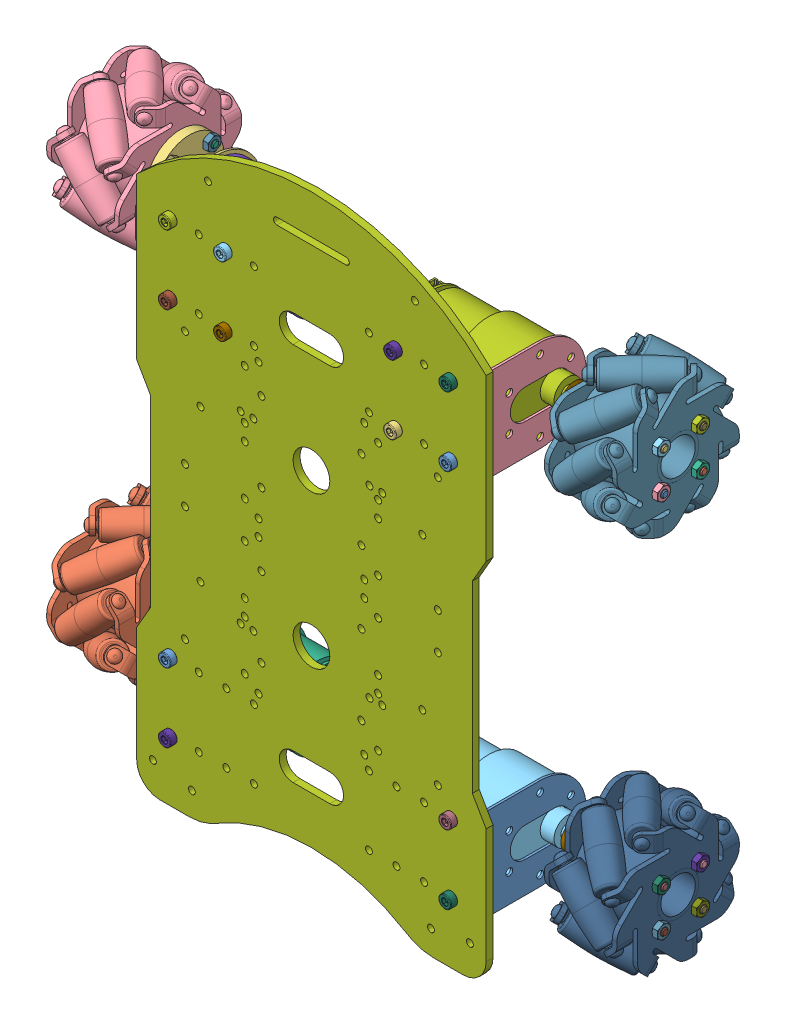
SolidWorks assembly mkbot_sw_carkit, configuration Varsayılan. Lengths in mm.
Overall size (254 262.05 67.79).
125 component instances, 97 part files, 0 mates.
Components (placement in the parent):
- Motor Brackets-1: Motor Brackets [Varsayılan] at origin size (142 205 45.5)
  - Motor Bracket_001-1: Motor Bracket_001 [Varsayılan] at (71 -115.5 -4) x (-1 0 0) z (0 0 -1) size (41 40 45.5)
  - Motor Bracket_002-1: Motor Bracket_002 [Varsayılan] at (-71 -115.5 -4) x (1 0 0) z (0 0 -1) size (41 40 45.5)
  - Motor Bracket_003-1: Motor Bracket_003 [Varsayılan] at (-71 49.5 -4) x (1 0 0) z (0 0 -1) size (41 40 45.5)
  - Motor Bracket_004-1: Motor Bracket_004 [Varsayılan] at (71 49.5 -4) x (-1 0 0) z (0 0 -1) size (41 40 45.5)
- Motors-1: Motors [Varsayılan] at origin size (182 202 37)
  - DC Gear Motor 37mm_001-1: DC Gear Motor 37mm_001 [Varsayılan] at (79 -115.5 -28.5) x (0 0 -1) z (1 0 0) size (37 37 73.8)
  - DC Gear Motor 37mm_002-1: DC Gear Motor 37mm_002 [Varsayılan] at (-79 -115.5 -28.5) x (0 0 -1) z (-1 0 0) size (37 37 73.8)
  - DC Gear Motor 37mm_003-1: DC Gear Motor 37mm_003 [Varsayılan] at (79 49.5 -28.5) x (0 0 -1) z (1 0 0) size (37 37 73.8)
  - DC Gear Motor 37mm_004-1: DC Gear Motor 37mm_004 [Varsayılan] at (-79 49.5 -28.5) x (0 0 -1) z (-1 0 0) size (37 37 73.8)
- Wheels-1: Wheels [Varsayılan] at origin size (254 223.31 58.31)
  - Rad_001-1: Rad_001 [Varsayılan] at (79 -115.5 -35.5) x (1 0 0) z (0 0 -1) size (48 58.31 58.31)
    - Rad 60mm_001-1: Rad 60mm_001 [Varsayılan] at (13.5 0 0) x (0 -1 0) z (0 0 1) size (58.31 48 58.31)
      - Rad Adapter_001-1: Rad Adapter_001 [Varsayılan] at origin size (30 33.5 30)
      - mecanum wheel_001-1: mecanum wheel_001 [Varsayılan] at (0 2 0) size (58.31 31.5 58.31)
      - Fasteners-1: Fasteners [Varsayılan] at origin size (23.35 44.66 22.5)
        - M3x41.5-ThreadedRod006-1: M3x41.5-ThreadedRod006 [Varsayılan] at (-8.5 -7 -8.5) x (0 0 -1) z (0 -1 0) size (3.03 3.03 41.5)
        - M3x41.5-ThreadedRod005-1: M3x41.5-ThreadedRod005 [Varsayılan] at (-8.5 -7 8.5) x (0 0 -1) z (0 -1 0) size (3.03 3.03 41.5)
        - M3x41.5-ThreadedRod004-1: M3x41.5-ThreadedRod004 [Varsayılan] at (8.5 -7 -8.5) x (0 0 -1) z (0 -1 0) size (3.03 3.03 41.5)
        - M3-Nut008-1: M3-Nut008 [Varsayılan] at (-8.5 31.5 -8.5) x (1 0 0) z (0 1 0) size (6.35 5.5 2.4)
        - M3-Nut007-1: M3-Nut007 [Varsayılan] at (8.5 31.5 -8.5) x (1 0 0) z (0 1 0) size (6.35 5.5 2.4)
        - M3-Nut006-1: M3-Nut006 [Varsayılan] at (-8.5 31.5 8.5) x (1 0 0) z (0 1 0) size (6.35 5.5 2.4)
        - M3-Nut005-1: M3-Nut005 [Varsayılan] at (8.5 31.5 8.5) x (1 0 0) z (0 1 0) size (6.35 5.5 2.4)
        - M3-Nut-1: M3-Nut [Varsayılan] at (-8.5 -4 -8.5) x (1 0 0) z (0 -1 0) size (6.35 5.5 2.4)
        - M3-Nut003-1: M3-Nut003 [Varsayılan] at (8.5 -4 -8.5) x (1 0 0) z (0 -1 0) size (6.35 5.5 2.4)
        - M3-Nut002-1: M3-Nut002 [Varsayılan] at (-8.5 -4 8.5) x (1 0 0) z (0 -1 0) size (6.35 5.5 2.4)
        - M3-Nut001-1: M3-Nut001 [Varsayılan] at (8.5 -4 8.5) x (1 0 0) z (0 -1 0) size (6.35 5.5 2.4)
        - M3x41.5-ThreadedRod-1: M3x41.5-ThreadedRod [Varsayılan] at (8.5 -7 8.5) x (0 0 -1) z (0 -1 0) size (3.03 3.03 41.5)
        - M2.5x6-Screw-1: M2.5x6-Screw [Varsayılan] at (0 -8.9 8) size (2.52 2.52 6.07)
  - Rad_002-1: Rad_002 [Varsayılan] at (-79 -115.5 -35.5) x (1 0 0) z (0 0 -1) size (48 58.31 58.31)
    - Rad 60mm_002-1: Rad 60mm_002 [Varsayılan] at (-13.5 0 0) x (0 1 0) z (0 0 1) size (58.31 48 58.31)
      - Rad Adapter_002-1: Rad Adapter_002 [Varsayılan] at origin size (30 33.5 30)
      - Fasteners001-1: Fasteners001 [Varsayılan] at origin size (23.35 44.66 22.5)
        - M3x41.5-ThreadedRod009-1: M3x41.5-ThreadedRod009 [Varsayılan] at (-8.5 -7 -8.5) x (0 0 -1) z (0 -1 0) size (3.03 3.03 41.5)
        - M3x41.5-ThreadedRod010-1: M3x41.5-ThreadedRod010 [Varsayılan] at (-8.5 -7 8.5) x (0 0 -1) z (0 -1 0) size (3.03 3.03 41.5)
        - M3x41.5-ThreadedRod007-1: M3x41.5-ThreadedRod007 [Varsayılan] at (8.5 -7 -8.5) x (0 0 -1) z (0 -1 0) size (3.03 3.03 41.5)
        - M3-Nut009-1: M3-Nut009 [Varsayılan] at (-8.5 31.5 -8.5) x (1 0 0) z (0 1 0) size (6.35 5.5 2.4)
        - M3-Nut013-1: M3-Nut013 [Varsayılan] at (8.5 31.5 -8.5) x (1 0 0) z (0 1 0) size (6.35 5.5 2.4)
        - M3-Nut010-1: M3-Nut010 [Varsayılan] at (-8.5 31.5 8.5) x (1 0 0) z (0 1 0) size (6.35 5.5 2.4)
        - M3-Nut012-1: M3-Nut012 [Varsayılan] at (8.5 31.5 8.5) x (1 0 0) z (0 1 0) size (6.35 5.5 2.4)
        - M3-Nut016-1: M3-Nut016 [Varsayılan] at (-8.5 -4 -8.5) x (1 0 0) z (0 -1 0) size (6.35 5.5 2.4)
        - M3-Nut015-1: M3-Nut015 [Varsayılan] at (8.5 -4 -8.5) x (1 0 0) z (0 -1 0) size (6.35 5.5 2.4)
        - M3-Nut011-1: M3-Nut011 [Varsayılan] at (-8.5 -4 8.5) x (1 0 0) z (0 -1 0) size (6.35 5.5 2.4)
        - M3-Nut014-1: M3-Nut014 [Varsayılan] at (8.5 -4 8.5) x (1 0 0) z (0 -1 0) size (6.35 5.5 2.4)
        - M3x41.5-ThreadedRod008-1: M3x41.5-ThreadedRod008 [Varsayılan] at (8.5 -7 8.5) x (0 0 -1) z (0 -1 0) size (3.03 3.03 41.5)
        - M2.5x6-Screw001-1: M2.5x6-Screw001 [Varsayılan] at (0 -8.9 8) size (2.52 2.52 6.07)
      - mecanum wheel_002 (Mirror #1)-1: mecanum wheel_002 (Mirror #1) [Varsayılan] x (-1 0 0) z (0 0 1) size (58.31 31.5 58.31)
  - Rad_003-1: Rad_003 [Varsayılan] at (-79 49.5 -35.5) x (-1 0 0) z (0 0 -1) size (48 58.31 58.31)
    - Rad 60mm_003-1: Rad 60mm_003 [Varsayılan] at (13.5 0 0) x (0 -1 0) z (0 0 1) size (58.31 48 58.31)
      - Rad Adapter_003-1: Rad Adapter_003 [Varsayılan] at origin size (30 33.5 30)
      - mecanum wheel_003-1: mecanum wheel_003 [Varsayılan] at (0 2 0) size (58.31 31.5 58.31)
      - Fasteners003-1: Fasteners003 [Varsayılan] at origin size (23.35 44.66 22.5)
        - M3x41.5-ThreadedRod016-1: M3x41.5-ThreadedRod016 [Varsayılan] at (-8.5 -7 -8.5) x (0 0 -1) z (0 -1 0) size (3.03 3.03 41.5)
        - M3x41.5-ThreadedRod018-1: M3x41.5-ThreadedRod018 [Varsayılan] at (-8.5 -7 8.5) x (0 0 -1) z (0 -1 0) size (3.03 3.03 41.5)
        - M3x41.5-ThreadedRod014-1: M3x41.5-ThreadedRod014 [Varsayılan] at (8.5 -7 -8.5) x (0 0 -1) z (0 -1 0) size (3.03 3.03 41.5)
        - M3-Nut028-1: M3-Nut028 [Varsayılan] at (-8.5 31.5 -8.5) x (1 0 0) z (0 1 0) size (6.35 5.5 2.4)
        - M3-Nut029-1: M3-Nut029 [Varsayılan] at (8.5 31.5 -8.5) x (1 0 0) z (0 1 0) size (6.35 5.5 2.4)
        - M3-Nut027-1: M3-Nut027 [Varsayılan] at (-8.5 31.5 8.5) x (1 0 0) z (0 1 0) size (6.35 5.5 2.4)
        - M3-Nut032-1: M3-Nut032 [Varsayılan] at (8.5 31.5 8.5) x (1 0 0) z (0 1 0) size (6.35 5.5 2.4)
        - M3-Nut024-1: M3-Nut024 [Varsayılan] at (-8.5 -4 -8.5) x (1 0 0) z (0 -1 0) size (6.35 5.5 2.4)
        - M3-Nut025-1: M3-Nut025 [Varsayılan] at (8.5 -4 -8.5) x (1 0 0) z (0 -1 0) size (6.35 5.5 2.4)
        - M3-Nut026-1: M3-Nut026 [Varsayılan] at (-8.5 -4 8.5) x (1 0 0) z (0 -1 0) size (6.35 5.5 2.4)
        - M3-Nut030-1: M3-Nut030 [Varsayılan] at (8.5 -4 8.5) x (1 0 0) z (0 -1 0) size (6.35 5.5 2.4)
        - M3x41.5-ThreadedRod015-1: M3x41.5-ThreadedRod015 [Varsayılan] at (8.5 -7 8.5) x (0 0 -1) z (0 -1 0) size (3.03 3.03 41.5)
        - M2.5x6-Screw003-1: M2.5x6-Screw003 [Varsayılan] at (0 -8.9 8) size (2.52 2.52 6.07)
  - Rad_004-1: Rad_004 [Varsayılan] at (79 49.5 -35.5) x (-1 0 0) z (0 0 -1) size (48 58.31 58.31)
    - Rad 60mm_004-1: Rad 60mm_004 [Varsayılan] at (-13.5 0 0) x (0 1 0) z (0 0 1) size (58.31 48 58.31)
      - Rad Adapter_004-1: Rad Adapter_004 [Varsayılan] at origin size (30 33.5 30)
      - Fasteners002-1: Fasteners002 [Varsayılan] at origin size (23.35 44.66 22.5)
        - M3x41.5-ThreadedRod012-1: M3x41.5-ThreadedRod012 [Varsayılan] at (-8.5 -7 -8.5) x (0 0 -1) z (0 -1 0) size (3.03 3.03 41.5)
        - M3x41.5-ThreadedRod013-1: M3x41.5-ThreadedRod013 [Varsayılan] at (-8.5 -7 8.5) x (0 0 -1) z (0 -1 0) size (3.03 3.03 41.5)
        - M3x41.5-ThreadedRod017-1: M3x41.5-ThreadedRod017 [Varsayılan] at (8.5 -7 -8.5) x (0 0 -1) z (0 -1 0) size (3.03 3.03 41.5)
        - M3-Nut031-1: M3-Nut031 [Varsayılan] at (-8.5 31.5 -8.5) x (1 0 0) z (0 1 0) size (6.35 5.5 2.4)
        - M3-Nut022-1: M3-Nut022 [Varsayılan] at (8.5 31.5 -8.5) x (1 0 0) z (0 1 0) size (6.35 5.5 2.4)
        - M3-Nut023-1: M3-Nut023 [Varsayılan] at (-8.5 31.5 8.5) x (1 0 0) z (0 1 0) size (6.35 5.5 2.4)
        - M3-Nut018-1: M3-Nut018 [Varsayılan] at (8.5 31.5 8.5) x (1 0 0) z (0 1 0) size (6.35 5.5 2.4)
        - M3-Nut021-1: M3-Nut021 [Varsayılan] at (-8.5 -4 -8.5) x (1 0 0) z (0 -1 0) size (6.35 5.5 2.4)
        - M3-Nut020-1: M3-Nut020 [Varsayılan] at (8.5 -4 -8.5) x (1 0 0) z (0 -1 0) size (6.35 5.5 2.4)
        - M3-Nut017-1: M3-Nut017 [Varsayılan] at (-8.5 -4 8.5) x (1 0 0) z (0 -1 0) size (6.35 5.5 2.4)
        - M3-Nut019-1: M3-Nut019 [Varsayılan] at (8.5 -4 8.5) x (1 0 0) z (0 -1 0) size (6.35 5.5 2.4)
        - M3x41.5-ThreadedRod011-1: M3x41.5-ThreadedRod011 [Varsayılan] at (8.5 -7 8.5) x (0 0 -1) z (0 -1 0) size (3.03 3.03 41.5)
        - M2.5x6-Screw002-1: M2.5x6-Screw002 [Varsayılan] at (0 -8.9 8) size (2.52 2.52 6.07)
      - mecanum wheel_002 (Mirror #1)001-1: mecanum wheel_002 (Mirror #1)001 [Varsayılan] x (-1 0 0) z (0 0 1) size (58.31 31.5 58.31)
- Fasteners005-1: Fasteners005 [Varsayılan] at origin size (128.35 200.5 13.14)
  - Screw and Nut M3x010_011-1: Screw and Nut M3x010_011 [Varsayılan] at (61 64.5 0) size (6.35 5.5 13.14)
    - M3x10-Screw010-1: M3x10-Screw010 [Varsayılan] at origin size (5.5 5.5 13.14)
    - M3-Nut042-1: M3-Nut042 [Varsayılan] at (0 0 -4) x (-1 0 0) z (0 0 -1) size (6.35 5.5 2.4)
  - Screw and Nut M3x010_022-1: Screw and Nut M3x010_022 [Varsayılan] at (37 64.5 0) size (6.35 5.5 13.14)
    - M3x10-Screw021-1: M3x10-Screw021 [Varsayılan] at origin size (5.5 5.5 13.14)
    - M3-Nut053-1: M3-Nut053 [Varsayılan] at (0 0 -4) x (-1 0 0) z (0 0 -1) size (6.35 5.5 2.4)
  - Screw and Nut M3x010_021-1: Screw and Nut M3x010_021 [Varsayılan] at (61 34.5 0) size (6.35 5.5 13.14)
    - M3x10-Screw020-1: M3x10-Screw020 [Varsayılan] at origin size (5.5 5.5 13.14)
    - M3-Nut052-1: M3-Nut052 [Varsayılan] at (0 0 -4) x (-1 0 0) z (0 0 -1) size (6.35 5.5 2.4)
  - Screw and Nut M3x010_020-1: Screw and Nut M3x010_020 [Varsayılan] at (37 34.5 0) size (6.35 5.5 13.14)
    - M3x10-Screw019-1: M3x10-Screw019 [Varsayılan] at origin size (5.5 5.5 13.14)
    - M3-Nut051-1: M3-Nut051 [Varsayılan] at (0 0 -4) x (-1 0 0) z (0 0 -1) size (6.35 5.5 2.4)
  - Screw and Nut M3x010_019-1: Screw and Nut M3x010_019 [Varsayılan] at (-37 64.5 0) size (6.35 5.5 13.14)
    - M3x10-Screw018-1: M3x10-Screw018 [Varsayılan] at origin size (5.5 5.5 13.14)
    - M3-Nut050-1: M3-Nut050 [Varsayılan] at (0 0 -4) x (-1 0 0) z (0 0 -1) size (6.35 5.5 2.4)
  - Screw and Nut M3x010_018-1: Screw and Nut M3x010_018 [Varsayılan] at (-61 64.5 0) size (6.35 5.5 13.14)
    - M3x10-Screw017-1: M3x10-Screw017 [Varsayılan] at origin size (5.5 5.5 13.14)
    - M3-Nut049-1: M3-Nut049 [Varsayılan] at (0 0 -4) x (-1 0 0) z (0 0 -1) size (6.35 5.5 2.4)
  - Screw and Nut M3x010_017-1: Screw and Nut M3x010_017 [Varsayılan] at (-37 34.5 0) size (6.35 5.5 13.14)
    - M3x10-Screw016-1: M3x10-Screw016 [Varsayılan] at origin size (5.5 5.5 13.14)
    - M3-Nut048-1: M3-Nut048 [Varsayılan] at (0 0 -4) x (-1 0 0) z (0 0 -1) size (6.35 5.5 2.4)
  - Screw and Nut M3x010_016-1: Screw and Nut M3x010_016 [Varsayılan] at (-61 34.5 0) size (6.35 5.5 13.14)
    - M3x10-Screw015-1: M3x10-Screw015 [Varsayılan] at origin size (5.5 5.5 13.14)
    - M3-Nut047-1: M3-Nut047 [Varsayılan] at (0 0 -4) x (-1 0 0) z (0 0 -1) size (6.35 5.5 2.4)
  - Screw and Nut M3x010_015-1: Screw and Nut M3x010_015 [Varsayılan] at (61 -100.5 0) size (6.35 5.5 13.14)
    - M3x10-Screw014-1: M3x10-Screw014 [Varsayılan] at origin size (5.5 5.5 13.14)
    - M3-Nut046-1: M3-Nut046 [Varsayılan] at (0 0 -4) x (-1 0 0) z (0 0 -1) size (6.35 5.5 2.4)
  - Screw and Nut M3x010_014-1: Screw and Nut M3x010_014 [Varsayılan] at (61 -130.5 0) size (6.35 5.5 13.14)
    - M3x10-Screw013-1: M3x10-Screw013 [Varsayılan] at origin size (5.5 5.5 13.14)
    - M3-Nut045-1: M3-Nut045 [Varsayılan] at (0 0 -4) x (-1 0 0) z (0 0 -1) size (6.35 5.5 2.4)
  - Screw and Nut M3x010_013-1: Screw and Nut M3x010_013 [Varsayılan] at (-61 -130.5 0) size (6.35 5.5 13.14)
    - M3x10-Screw012-1: M3x10-Screw012 [Varsayılan] at origin size (5.5 5.5 13.14)
    - M3-Nut044-1: M3-Nut044 [Varsayılan] at (0 0 -4) x (-1 0 0) z (0 0 -1) size (6.35 5.5 2.4)
  - Screw and Nut M3x010_012-1: Screw and Nut M3x010_012 [Varsayılan] at (-61 -100.5 0) size (6.35 5.5 13.14)
    - M3x10-Screw011-1: M3x10-Screw011 [Varsayılan] at origin size (5.5 5.5 13.14)
    - M3-Nut043-1: M3-Nut043 [Varsayılan] at (0 0 -4) x (-1 0 0) z (0 0 -1) size (6.35 5.5 2.4)
  - M3-Nut058-1: M3-Nut058 [Varsayılan] at (-37 -100.5 -4) x (-1 0 0) z (0 0 -1) size (6.35 5.5 2.4)
  - M3-Nut059-1: M3-Nut059 [Varsayılan] at (-37 -130.5 -4) x (-1 0 0) z (0 0 -1) size (6.35 5.5 2.4)
  - M3-Nut060-1: M3-Nut060 [Varsayılan] at (37 -100.5 -4) x (-1 0 0) z (0 0 -1) size (6.35 5.5 2.4)
  - M3-Nut066-1: M3-Nut066 [Varsayılan] at (37 -130.5 -4) x (-1 0 0) z (0 0 -1) size (6.35 5.5 2.4)
- Grundplatte-1: Grundplatte [Varsayılan] at (0 0 -2) x (-1 0 0) z (0 0 1) size (152 262.05 3)
